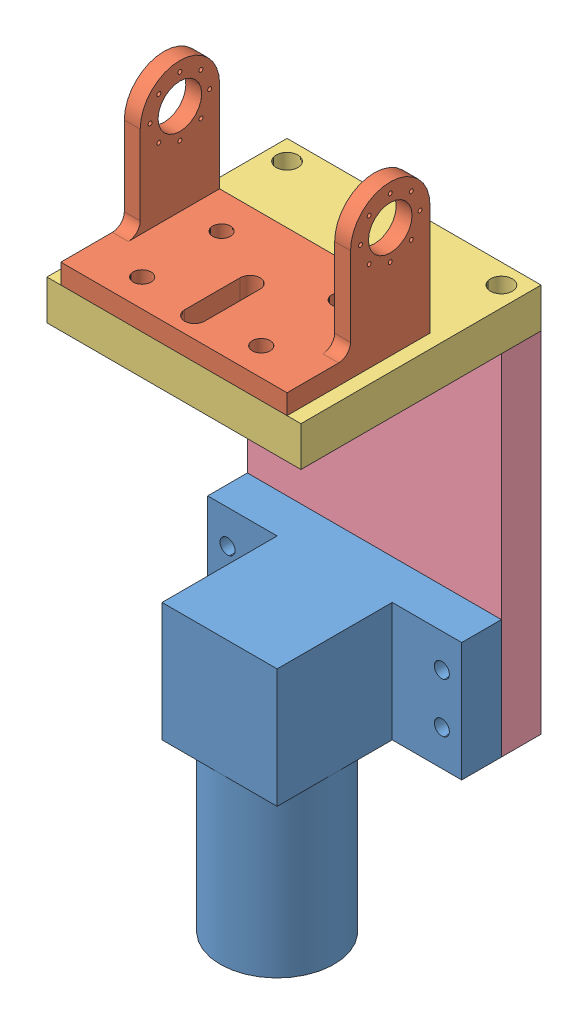
SolidWorks assembly Assem1, configuration Default. Lengths in mm.
Overall size (64 177.8 60.5).
4 component instances, 4 part files, 8 mates.
Components (placement in the parent):
- camara-1: camara [Default] at (25.4666 61.7411 34.526) size (64 71.8 40)
- suporte-1: suporte [Default] at (25.4666 144.7411 67.026) x (1 0 0) z (0 -1 0) size (57 36 38)
- L-parte1-1: L-parte1 [Default] at (57.4666 144.7411 24.526) x (-1 0 0) z (0 1 0) size (64 60.5 10)
- L-parte2-1: L-parte2 [Default] at (57.4666 144.7411 24.526) x (-1 0 0) z (0 1 0) size (64 10 88)
Mates (geometry in assembly coordinates):
- Parallel2: parallel anti-aligned: plane of camara-1 through (-6.5334 76.7411 44.526) normal (0 1 0); plane of suporte-1 through (25.4666 144.7411 67.026) normal (0 -1 0)
- Distance1: distance = 11.5 mm aligned: plane of camara-1 through (10.9666 76.7411 73.526) normal (0 0 1); plane of suporte-1 through (-3.0334 149.7411 85.026) normal (0 0 1)
- Coincident1: coincident anti-aligned: plane of suporte-1 through (25.4666 144.7411 67.026) normal (0 -1 0); plane of L-parte1-1 through (-6.5334 144.7411 85.026) normal (0 1 0)
- Concentric1: concentric aligned: circle of suporte-1; circle of L-parte1-1
- Concentric2: concentric aligned: circle of suporte-1; circle of L-parte1-1
- Coincident2: coincident anti-aligned: plane of camara-1 through (25.4666 61.7411 34.526) normal (0 0 -1); plane of L-parte2-1 through (-6.5334 46.7411 34.526) normal (0 0 1)
- Coincident3: coincident aligned: plane of camara-1 through (-6.5334 46.7411 44.526) normal (0 -1 0); plane of L-parte2-1 through (-6.5334 46.7411 24.526) normal (0 -1 0)
- Coincident4: coincident aligned: plane of camara-1 through (-6.5334 46.7411 44.526) normal (-1 0 0); plane of L-parte2-1 through (-6.5334 144.7411 24.526) normal (-1 0 0)
